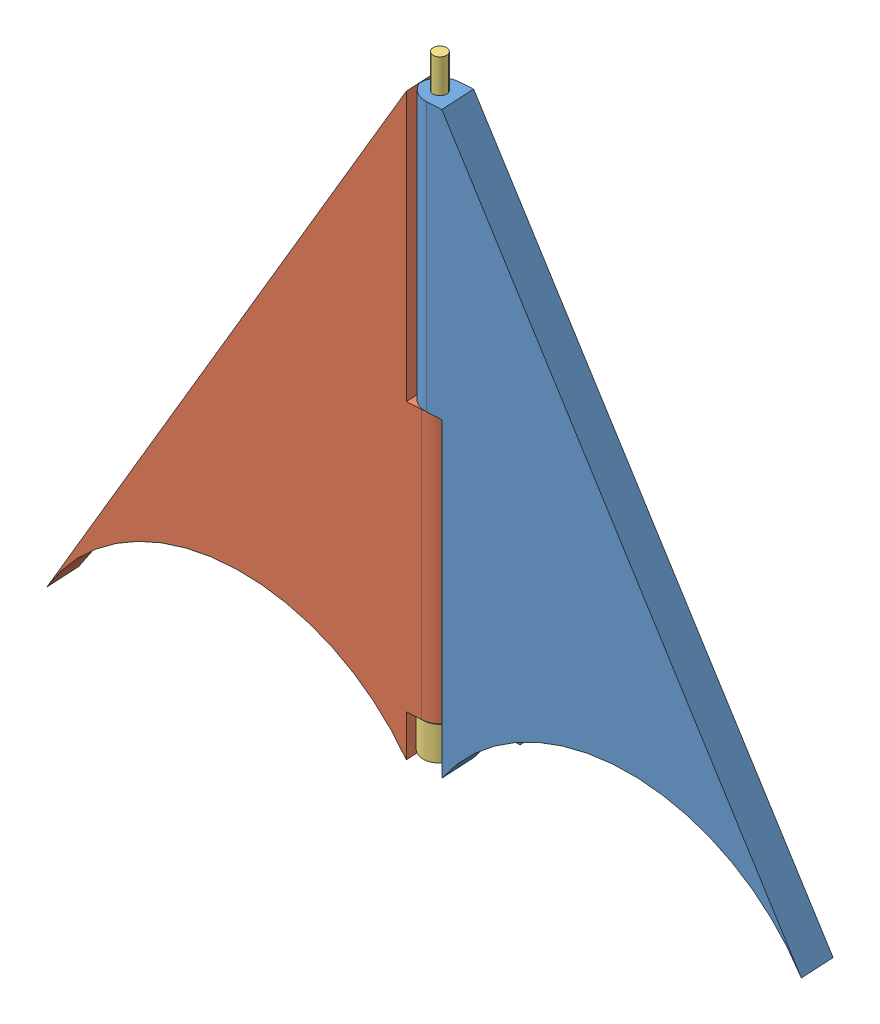
SolidWorks assembly Canard_patte, configuration Défaut. Lengths in mm.
Overall size (106.85 92.94 10.73).
3 component instances, 3 part files, 7 mates.
Components (placement in the parent):
- canard_palme_1-1: canard_palme_1 [Défaut] at (-0.1738 0.01 -1.4659) x (0.998556 0 -0.053723) z (0.053723 0 0.998556) size (55.85 87.96 5)
- canard_palme_2-1: canard_palme_2 [Défaut] at (-54.5092 0 6.4646) x (-0.998556 0 0.053723) z (-0.053723 0 -0.998556) size (55.85 87.96 5)
- arret_rotation-1: arret_rotation [Défaut] at (-27.3532 2.4899 2.5) x (-0.053723 0 -0.998556) z (0 1 0) size (6 18.23 90)
Mates (geometry in assembly coordinates):
- Parallèle1: parallel anti-aligned: plane of canard_palme_1-1 through (-0.1738 47.4999 -1.4659) normal (0 -1 0); plane of canard_palme_2-1 through (-54.0759 47.4899 8.7502) normal (0 1 0)
- Coaxiale1: concentric aligned: cylinder of canard_palme_1-1 through (-27.3532 47.4999 2.5) axis (0 1 0) radius 1.0093; circle of canard_palme_2-1
- Coaxiale2: concentric anti-aligned: circle of canard_palme_2-1; cylinder of arret_rotation-1 through (-27.3532 92.4899 2.5) axis (0 -1 0) radius 0.9974
- Distance2: distance = 0 mm anti-aligned: plane of arret_rotation-1 through (-27.3532 7.4899 2.5) normal (0 1 0); plane of canard_palme_2-1 through (-54.5092 7.4899 6.4646) normal (0 -1 0)
- Distance4: distance = 0.01 mm anti-aligned: plane of canard_palme_1-1 through (-0.1738 47.4999 -1.4659) normal (0 -1 0); plane of canard_palme_2-1 through (-54.5092 47.4899 6.4646) normal (0 1 0)
- AngleLimite2: limit planar angle = 1.570796 rad anti-aligned: plane of canard_palme_1-1 through (-0.1203 -15.4541 -1.4688) normal (-0.053723 0 -0.998556); plane of arret_rotation-1 through (-18.4384 6.0805 -1.4847) normal (0.998556 0 -0.053723)
- AngleLimite3: limit planar angle = 1.570796 rad anti-aligned: plane of canard_palme_2-1 through (-54.8313 -15.4641 1.4747) normal (-0.053723 0 -0.998556); plane of arret_rotation-1 through (-36.644 6.0805 -0.5052) normal (-0.998556 0 0.053723)
